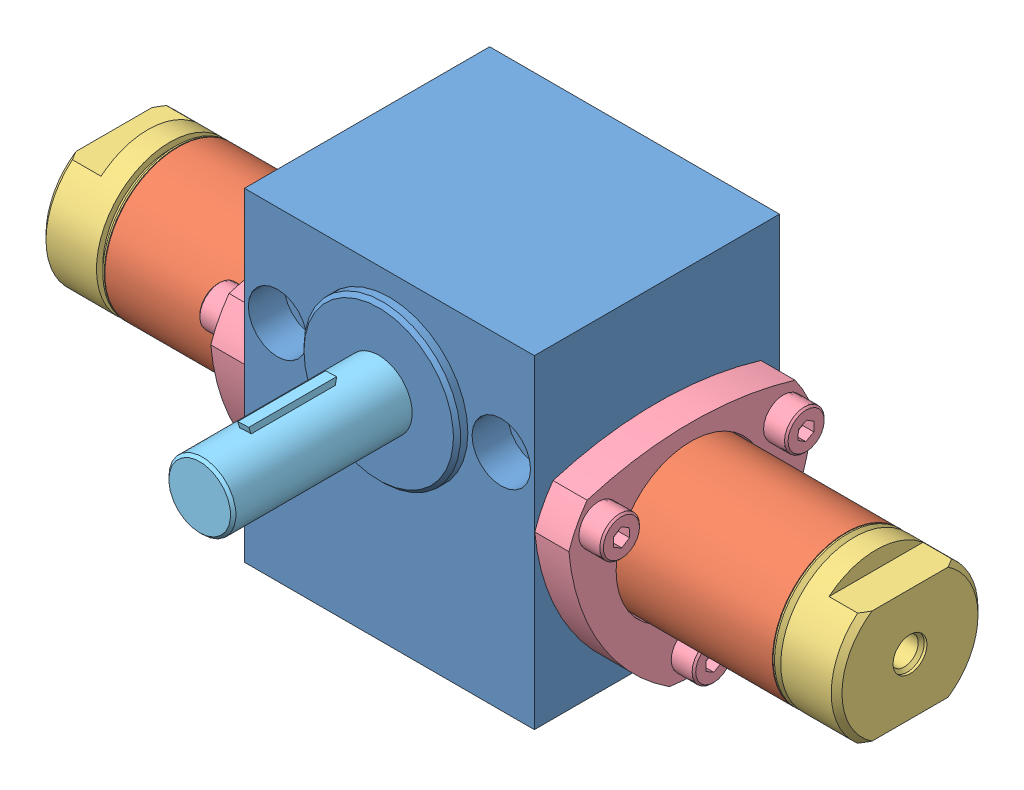
SolidWorks assembly PT-017090, configuration Default. Lengths in mm.
Overall size (112.98 45.97 61.72).
8 component instances, 5 part files, 20 mates.
Components (placement in the parent):
- 017SB-actuator_body-1: 017SB-actuator_body [Default] at (0 -18.542 0) size (41.15 45.97 36.32)
- D-33057-1_102-1: D-33057-1_102 [Default] at (-48.5648 0 0) size (27.99 20.83 20.83)
- D-4237S-PT-rear_head-1: D-4237S-PT-rear_head [Default] at (-43.0022 0 0) x (-1 0 0) z (0 1 0) size (13.49 20.83 20.83)
- 017-retainer_ring-1: 017-retainer_ring [Default] at (-20.574 0 0) x (-1 0 0) z (0 0 -1) size (8.06 31.22 34.68)
- D-33057-1_102-2: D-33057-1_102 [Default] at (48.5648 0 0) x (-1 0 0) z (0 0 1) size (27.99 20.83 20.83)
- D-4237S-PT-rear_head-2: D-4237S-PT-rear_head [Default] at (43.0022 0 0) x (1 0 0) z (0 -1 0) size (13.49 20.83 20.83)
- 017-retainer_ring-2: 017-retainer_ring [Default] at (20.574 0 0) size (8.06 31.22 34.68)
- 0_75-shaft-1: 0_75-shaft [Default] at (0 13.208 0) x (0.998651 0.05193 0) z (0 0 1) size (9.53 10.34 61.72)
Mates (geometry in assembly coordinates):
- Distance2: distance = 0 mm aligned: plane of D-33057-1_102-1 through (-20.574 0 0) normal (1 0 0); plane of 017SB-actuator_body-1 through (-20.574 -18.542 0) normal (1 0 0)
- Coincident1: coincident aligned: line of 017SB-actuator_body-1 through (80.9 0 0) axis (-1 0 0); line of D-33057-1_102-1 through (32.3352 0 0) axis (-1 0 0)
- Angle3: planar angle = 0 rad aligned: plane of D-33057-1_102-1 through (-48.5648 0 0) normal (0 0 -1); plane of 017SB-actuator_body-1 through (0 -18.542 0) normal (0 0 -1)
- Distance3: distance = 0 mm anti-aligned: plane of D-4237S-PT-rear_head-1; plane of D-33057-1_102-1 through (-47.0408 0 0) normal (1 0 0)
- Coincident2: coincident anti-aligned: line of D-33057-1_102-1 through (32.3352 0 0) axis (-1 0 0); line of D-4237S-PT-rear_head-1 through (-123.9022 0 0) axis (1 0 0)
- Angle5: planar angle = 1.570796 rad anti-aligned: plane of D-4237S-PT-rear_head-1; plane of D-33057-1_102-1 through (-48.5648 0 0) normal (0 0 -1)
- Distance4: distance = 0 mm anti-aligned: plane of 017-retainer_ring-1 through (-20.574 0 0) normal (-1 0 0); plane of 017SB-actuator_body-1 through (-20.574 -18.542 0) normal (1 0 0)
- Coincident3: coincident anti-aligned: line of 017SB-actuator_body-1 through (80.9 0 0) axis (-1 0 0); line of 017-retainer_ring-1 through (-101.474 0 0) axis (1 0 0)
- Angle6: planar angle = 0 rad anti-aligned: plane of 017-retainer_ring-1 through (-20.574 0 0) normal (0 0 1); plane of 017SB-actuator_body-1 through (0 -18.542 0) normal (0 0 -1)
- Distance5: distance = 0 mm anti-aligned: plane of D-33057-1_102-2; plane of 017SB-actuator_body-1 through (20.574 -18.542 0) normal (1 0 0)
- Coincident4: coincident anti-aligned: line of 017SB-actuator_body-1 through (80.9 0 0) axis (-1 0 0); line of D-33057-1_102-2 through (-32.3352 0 0) axis (1 0 0)
- Angle9: planar angle = 0 rad aligned: plane of D-33057-1_102-2 through (48.5648 0 0) normal (0 0 -1); plane of 017SB-actuator_body-1 through (0 -18.542 0) normal (0 0 -1)
- Distance6: distance = 0 mm anti-aligned: plane of D-4237S-PT-rear_head-2; plane of D-33057-1_102-2
- Coincident5: coincident anti-aligned: line of D-33057-1_102-2 through (-32.3352 0 0) axis (1 0 0); line of D-4237S-PT-rear_head-2 through (123.9022 0 0) axis (-1 0 0)
- Angle11: planar angle = 1.570796 rad anti-aligned: plane of D-4237S-PT-rear_head-2; plane of D-33057-1_102-2 through (48.5648 0 0) normal (0 0 -1)
- Distance8: distance = 0 mm aligned: plane of 017-retainer_ring-2 through (20.574 0 0) normal (1 0 0); plane of 017SB-actuator_body-1 through (20.574 -18.542 0) normal (1 0 0)
- Coincident6: coincident aligned: line of 017SB-actuator_body-1 through (80.9 0 0) axis (-1 0 0); line of 017-retainer_ring-2 through (101.474 0 0) axis (-1 0 0)
- Angle14: planar angle = 0 rad aligned: plane of 017-retainer_ring-2 through (20.574 0 0) normal (0 0 -1); plane of 017SB-actuator_body-1 through (0 -18.542 0) normal (0 0 -1)
- Coincident8: coincident aligned: plane of 017SB-actuator_body-1 through (0 -18.542 44.323) normal (0 0 1); plane of 0_75-shaft-1 through (0 13.208 44.323) normal (0 0 1)
- Coincident9: coincident aligned: line of 017SB-actuator_body-1 through (0 13.208 80.9) axis (0 0 -1); line of 0_75-shaft-1 through (0 13.208 80.9) axis (0 0 -1)
